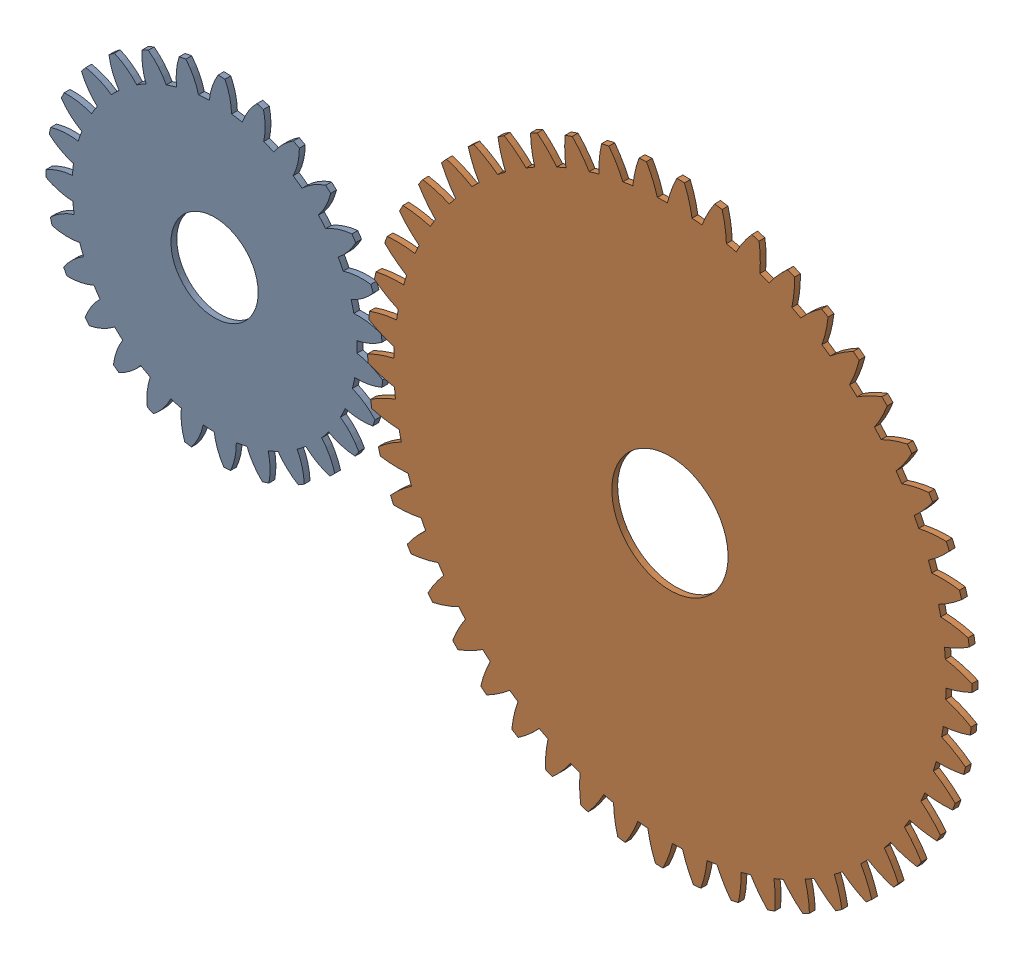
SolidWorks assembly final_assem, configuration Default. Lengths in mm.
Overall size (534.6 409.58 3).
2 component instances, 2 part files, 5 mates.
Components (placement in the parent):
- g3-3: g3 [Metric - Spur gear 6M 27T 20PA 3FW ---S27N75H50L45N] at (-116.5838 -15.8413 3) x (0 0 -1) z (0.099331 0.995054 0) size (3 173.6 173.87)
- Metric - Spur gear 6M 50T 20PA 3FW ---S50N75H50L60N-1: Metric - Spur gear 6M 50T 20PA 3FW ---S50N75H50L60N [Metric - Spur gear 6M 50T 20PA 3FW ---S50N75H50L60N] at (118.4162 -12.6041 3) x (0 0 -1) z (0.919371 0.393392 0) size (3 312 312)
Mates (geometry in assembly coordinates):
- Coincident2: coincident: point of g3-3; point of assembly
- Coincident3: coincident: point of Metric - Spur gear 6M 50T 20PA 3FW ---S50N75H50L60N-1; point of assembly
- Parallel1: parallel aligned: plane of g3-3 through (-116.5838 -15.8413 3) normal (0 0 1); plane of Metric - Spur gear 6M 50T 20PA 3FW ---S50N75H50L60N-1 through (118.4162 -12.6041 3) normal (0 0 1)
- Parallel2: parallel anti-aligned: plane of g3-3 through (-116.5838 -15.8413 3) normal (0 0 -1)
- Parallel3: parallel anti-aligned: plane of Metric - Spur gear 6M 50T 20PA 3FW ---S50N75H50L60N-1 through (118.4162 -12.6041 3) normal (0 0 -1)
